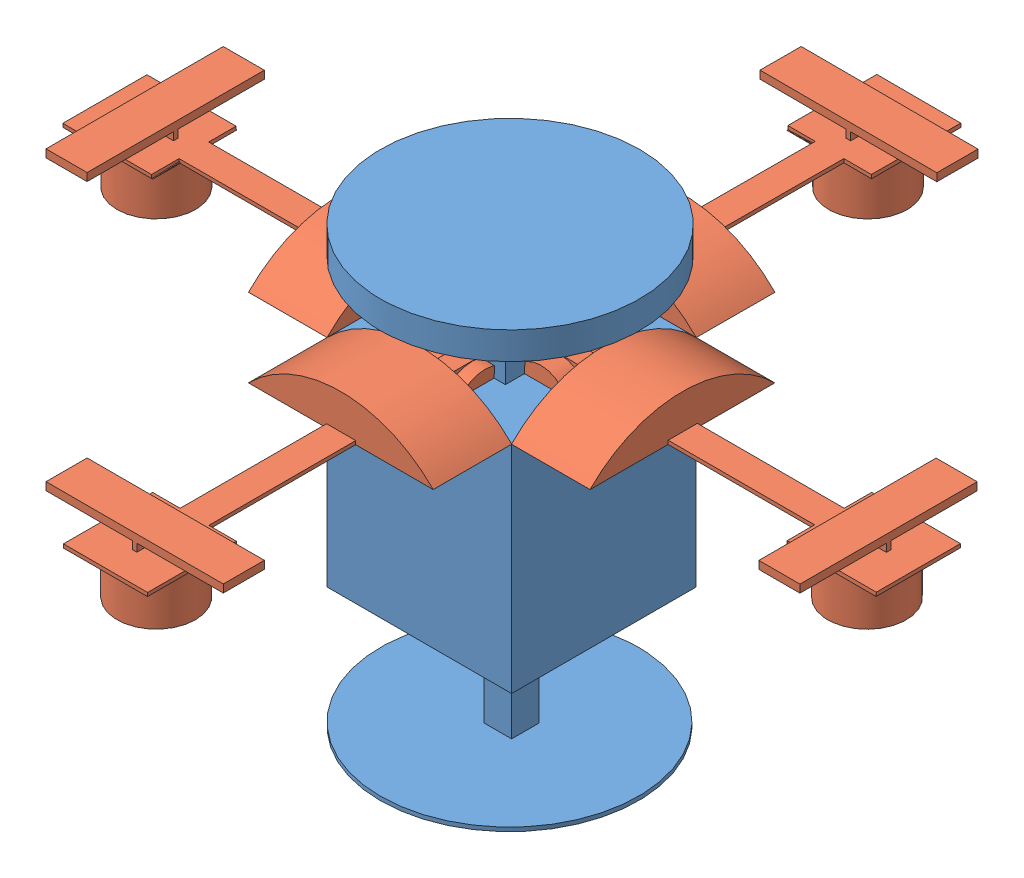
SolidWorks assembly Assem2, configuration Default. Lengths in mm.
Overall size (207.01 111 207.13).
5 component instances, 2 part files, 7 mates.
Components (placement in the parent):
- Part1-1: Part1 [Default] at (13.7374 -0.6868 112.0514) size (66.19 111 66.06)
- Part2-1: Part2 [Default] at (80.7356 61.164 88.5714) x (0.00008 0.999152 -0.041185) z (0.000003 0.041185 0.999152) size (22.27 97.36 47)
- Part2-2: Part2 [Default] at (37.2574 61.1704 132.057) x (0.041185 0.999152 -0.000241) z (-0.999152 0.041185 -0.00001) size (22.27 97.36 47)
- Part2-3: Part2 [Default] at (-6.2454 61.1508 88.5315) x (-0.00074 0.999151 0.041185) z (-0.000031 0.041185 -0.999152) size (22.27 97.36 47)
- Part2-6: Part2 [Default] at (37.2718 61.1632 44.9904) x (-0.041184 0.999152 -0.00023) z (0.999148 0.041185 0.002705) size (22.27 97.36 47)
Mates (geometry in assembly coordinates):
- Coincident2: coincident anti-aligned: line of Part1-1 through (60.7374 84.3132 112.0514) axis (0 0 -1); line of Part2-1 through (60.7374 84.3132 65.0514) axis (0 0 1)
- Coincident3: coincident: line of Part1-1 through (60.7374 84.3132 65.0514) axis (-1 0 0); point of Part2-1
- Coincident5: coincident anti-aligned: line of Part1-1 through (13.7374 84.3132 112.0514) axis (1 0 0); line of Part2-2 through (60.7773 84.3132 112.0514) axis (-1 0 0)
- Coincident6: coincident: line of Part1-1 through (13.7374 84.3132 65.0514) axis (0 0 1); point of Part2-2
- Coincident14: coincident: point of Part1-1; point of Part2-3
- Coincident17: coincident anti-aligned: line of Part1-1 through (13.7374 84.3132 65.0514) axis (0 0 1); line of Part2-3 through (13.7374 84.3132 112.0514) axis (0 0 -1)
- Coincident34: coincident: point of Part1-1; point of Part2-6
